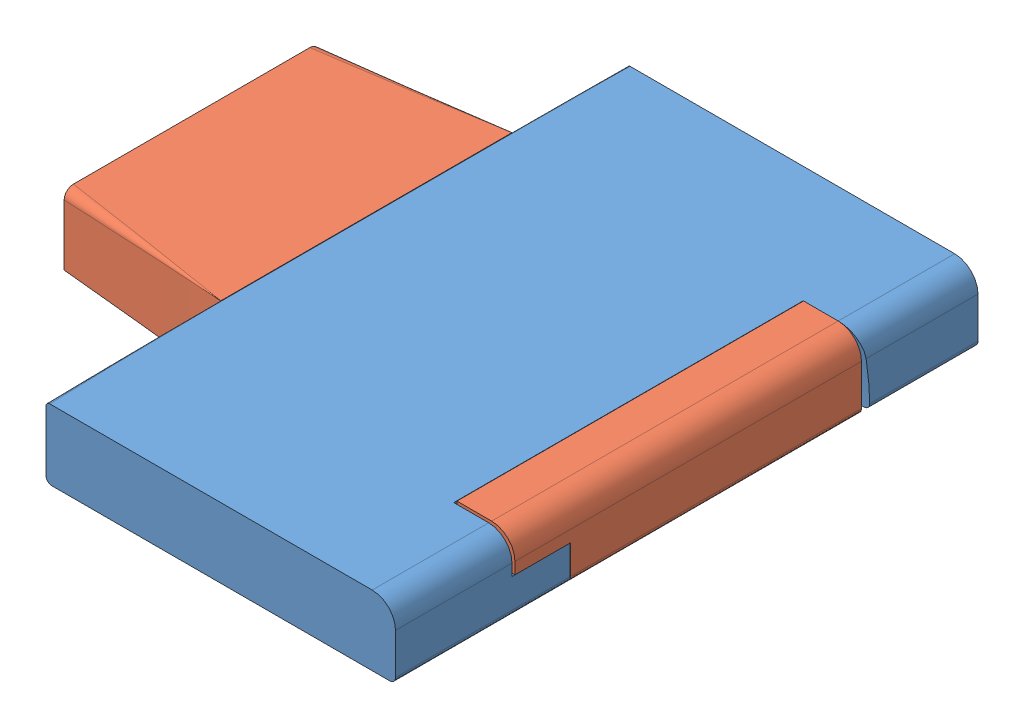
SolidWorks assembly test_mate_assembly, configuration Default. Lengths in mm.
Overall size (45.19 6.07 50).
2 component instances, 2 part files, 2 mates.
Components (placement in the parent):
- Right_Side_mate_test-2: Right_Side_mate_test [Default] at (24.3302 93.314 -55.9209) size (30.06 6.05 50)
- Center_mate_test-1: Center_mate_test [Default] at (39.3302 29.3326 -66.6519) x (0 0 1) z (-1 0 0) size (29.76 6.05 45.17)
Mates (geometry in assembly coordinates):
- Coincident1: coincident: point of ?; point of ?
- Coincident2: coincident: point of Right_Side_mate_test-2; point of Center_mate_test-1
